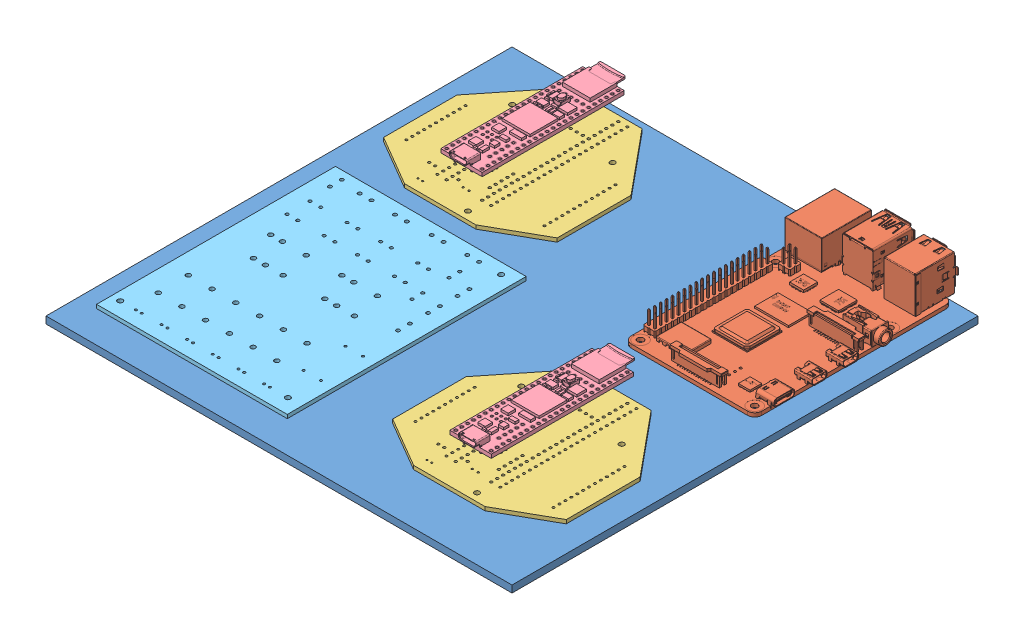
SolidWorks assembly Assemblage_PRM_cartes électronique_1, configuration Défaut. Lengths in mm.
Overall size (230 25.8 233).
13 component instances, 5 part files, 14 mates.
Components (placement in the parent):
- plaque_cartes_électroniques_1-1: plaque_cartes_électroniques_1 [Défaut] at (-95.3673 17.7358 300) size (230 3 233)
- Raspberry Pi 4 Model B-1: Raspberry Pi 4 Model B [Défaut] at (72.1982 26.5358 148.9026) x (0 0 -1) z (1 0 0) size (88.99 19.9 58.4)
- Teensy-Sheild-1: Teensy-Sheild [Défaut] at (-0.3508 25.7358 379.5257) x (0 0 -1) z (0 1 0) size (71.4 74.6 1.6)
  - Teensy-Sheild.step-1: Teensy-Sheild.step [Défaut] at origin size (71.4 74.6 1.6)
    - Teensy Sheild PCB.step-1: Teensy Sheild PCB.step [Défaut] at origin size (71.4 74.6 1.6)
- CIRCUIT BOARD,TEENSY 4.10-1: CIRCUIT BOARD,TEENSY 4.10 [Défaut] at (60.8492 37.3348 243.5257) x (0 0 -1) z (0 1 0) size (66.56 17.78 5.27)
- CIRCUIT BOARD,TEENSY 4.10-4: CIRCUIT BOARD,TEENSY 4.10 [Défaut] at (-45.3756 37.7504 141.201) x (0 0 -1) z (0 1 0) size (66.56 17.78 5.27)
- Teensy-Sheild-4: Teensy-Sheild [Défaut] at (-106.5756 26.1514 277.201) x (0 0 -1) z (0 1 0) size (71.4 74.6 1.6)
  - Teensy-Sheild.step-1: Teensy-Sheild.step [Défaut] at origin size (71.4 74.6 1.6)
    - Teensy Sheild PCB.step-1: Teensy Sheild PCB.step [Défaut] at origin size (71.4 74.6 1.6)
- Carte-mère-1: Carte-mère [Défaut] at (34.7329 25.7358 136.5593) x (0 0 1) z (0 1 0) size (102.53 81.84 1.6)
  - Carte-mère.step-1: Carte-mère.step [Défaut] at origin size (102.53 81.84 1.6)
    - Carte m____re PCB.step-1: Carte m____re PCB.step [Défaut] at origin size (102.53 81.84 1.6)
Mates (geometry in assembly coordinates):
- Distance1: distance = 5 mm anti-aligned: plane of Raspberry Pi 4 Model B-1 through (72.1982 25.7358 148.9026) normal (0 -1 0); plane of plaque_cartes_électroniques_1-1 through (-95.3673 20.7358 300) normal (0 1 0)
- Parallèle4: parallel anti-aligned: plane of plaque_cartes_électroniques_1-1 through (134.6327 20.7358 300) normal (1 0 0); plane of Raspberry Pi 4 Model B-1 through (44.1982 27.3358 191.4026) normal (-1 0 0)
- Parallèle5: parallel aligned: plane of plaque_cartes_électroniques_1-1 through (-95.3673 20.7358 67) normal (0 0 -1); plane of Raspberry Pi 4 Model B-1 through (44.1982 27.3358 106.4026) normal (0 0 -1)
- Parallèle9: parallel anti-aligned: plane of plaque_cartes_électroniques_1-1 through (-95.3673 20.7358 300) normal (0 1 0); plane of Teensy-Sheild-1/Teensy-Sheild.step-1/Teensy Sheild PCB.step-1 through (61.2071 25.7358 249.1787) normal (0 -1 0)
- Parallèle10: parallel aligned: plane of plaque_cartes_électroniques_1-1 through (-95.3673 20.7358 300) normal (0 0 1); plane of Teensy-Sheild-1/Teensy-Sheild.step-1/Teensy Sheild PCB.step-1 through (76.2492 25.7358 283.2257) normal (0 0 1)
- Distance4: distance = 5 mm anti-aligned: plane of Teensy-Sheild-1/Teensy-Sheild.step-1/Teensy Sheild PCB.step-1 through (61.2071 25.7358 249.1787) normal (0 -1 0); plane of plaque_cartes_électroniques_1-1 through (-95.3673 20.7358 300) normal (0 1 0)
- Parallèle11: parallel aligned: plane of Teensy-Sheild-1/Teensy-Sheild.step-1/Teensy Sheild PCB.step-1 through (45.6492 25.7358 211.8257) normal (0 0 -1); plane of CIRCUIT BOARD,TEENSY 4.10-1 through (51.9592 38.9338 213.0457) normal (0 0 -1)
- Coaxiale1: concentric aligned: circle of Teensy-Sheild-1/Teensy-Sheild.step-1/Teensy Sheild PCB.step-1; circle of CIRCUIT BOARD,TEENSY 4.10-1
- Distance5: distance = 10 mm anti-aligned: plane of Teensy-Sheild-1/Teensy-Sheild.step-1/Teensy Sheild PCB.step-1 through (61.2071 27.3358 249.1787) normal (0 1 0); plane of CIRCUIT BOARD,TEENSY 4.10-1 through (68.4692 37.3358 272.7357) normal (0 -1 0)
- Parallèle14: parallel aligned: plane of CIRCUIT BOARD,TEENSY 4.10-4 through (-54.2656 39.3494 110.721) normal (0 0 -1); plane of Teensy-Sheild-4/Teensy-Sheild.step-1/Teensy Sheild PCB.step-1 through (-60.5756 26.1514 109.501) normal (0 0 -1)
- Coaxiale4: concentric aligned: circle of CIRCUIT BOARD,TEENSY 4.10-4; circle of Teensy-Sheild-4/Teensy-Sheild.step-1/Teensy Sheild PCB.step-1
- Distance8: distance = 10 mm anti-aligned: plane of Teensy-Sheild-4/Teensy-Sheild.step-1/Teensy Sheild PCB.step-1 through (-45.0178 27.7514 146.854) normal (0 1 0); plane of CIRCUIT BOARD,TEENSY 4.10-4 through (-37.7556 37.7514 170.411) normal (0 -1 0)
- Distance9: distance = 5 mm anti-aligned: plane of Carte-mère-1/Carte-mère.step-1/Carte m____re PCB.step-1 through (-41.3271 25.7358 240.1443) normal (0 -1 0); plane of plaque_cartes_électroniques_1-1 through (-95.3673 20.7358 300) normal (0 1 0)
- Parallèle16: parallel aligned: plane of plaque_cartes_électroniques_1-1 through (-95.3673 20.7358 300) normal (0 0 1); plane of Carte-mère-1/Carte-mère.step-1/Carte m____re PCB.step-1 through (-0.4071 25.7358 291.4093) normal (0 0 1)
